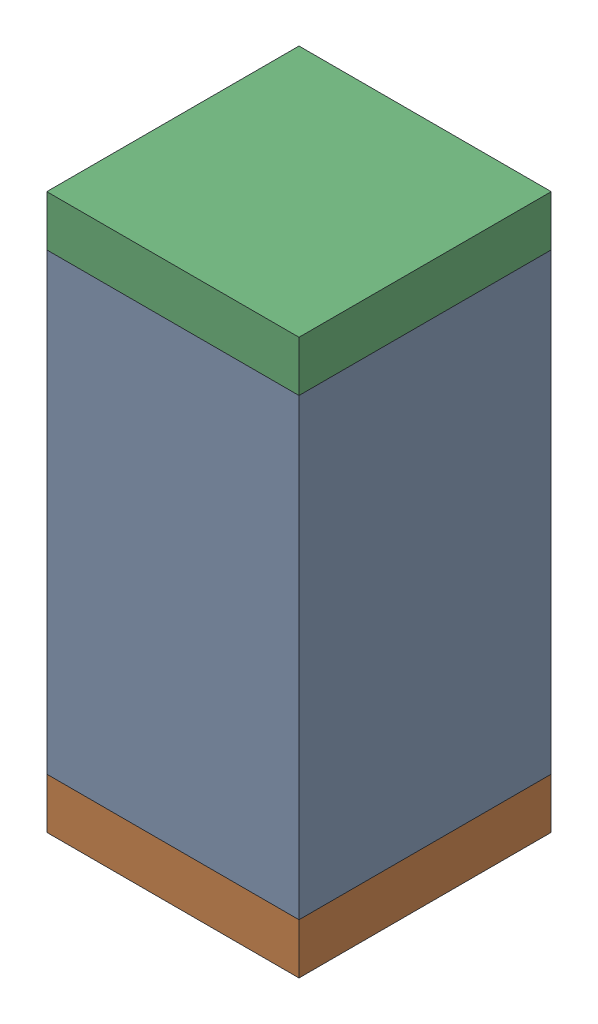
SolidWorks assembly C57, configuration Default. Lengths in mm.
Overall size (0.5 1.1 0.5).
6 component instances, 2 part files, 0 mates.
Components (placement in the parent):
- 791586336-1: 791586336 [Default] at (113.35 51.55 0) size (0.5 0.9 0.5)
  - Extruded_8-1: Extruded_8 [Default] at origin size (0.5 0.9 0.5)
- 810157360-1: 810157360 [Default] at (113.35 51.05 0) size (0.5 0.1 0.5)
  - Extruded_9-1: Extruded_9 [Default] at origin size (0.5 0.1 0.5)
- 810157360-2: 810157360 [Default] at (113.35 52.05 0) size (0.5 0.1 0.5)
  - Extruded_9-1: Extruded_9 [Default] at origin size (0.5 0.1 0.5)
